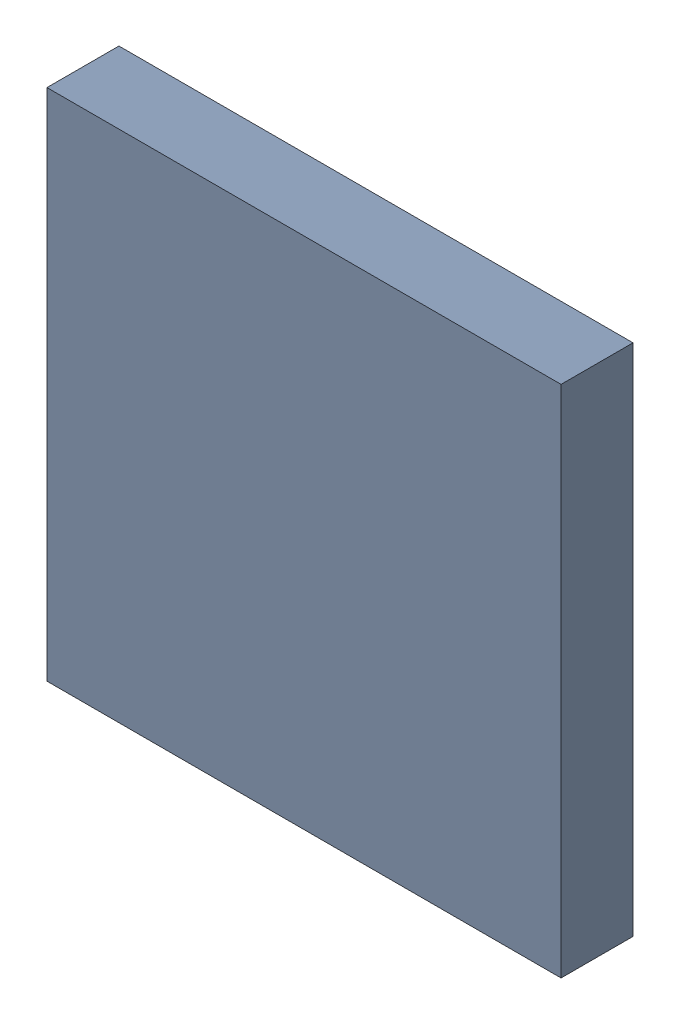
SolidWorks assembly U1, configuration Default. Lengths in mm.
Overall size (10 10 1.4).
2 component instances, 1 part files, 0 mates.
Components (placement in the parent):
- 642238864-1: 642238864 [Default] at (47 42 0.05) size (10 10 1.4)
  - Extruded_3-1: Extruded_3 [Default] at origin size (10 10 1.4)
